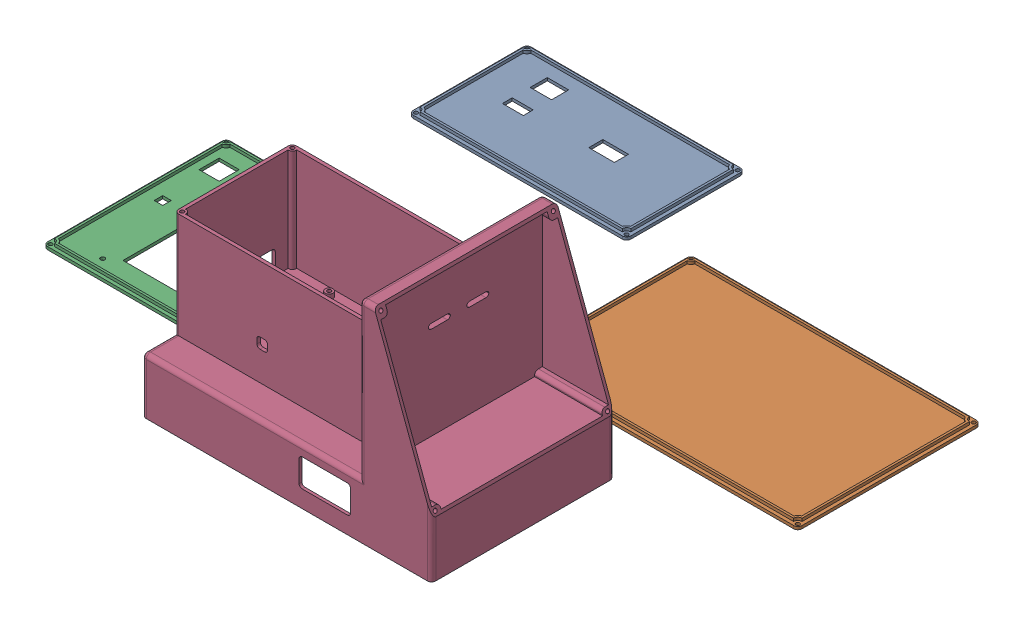
SolidWorks assembly Assembly PCB Box, configuration Default. Lengths in mm.
Overall size (370.19 125.12 303.92).
4 component instances, 4 part files, 4 mates.
Components (placement in the parent):
- pcb box lid-1: pcb box lid [Default] at (-27.4267 33.4367 83.8506) size (129.29 3.4 70.1)
- power supply lid-1: power supply lid [Default] at (129.7431 33.4367 181.9969) size (172.06 3.4 108.56)
- screen lid-1: screen lid [Default] at (-68.3866 33.4367 260.1209) size (96.52 3.4 108.56)
- pcb box main-3: pcb box main [Default] at (47.7522 66.4567 210.5523) size (172.06 125.12 108.56)
Mates (geometry in assembly coordinates):
- Coincident2: coincident aligned: plane of pcb box lid-1 through (-27.4267 31.7367 83.8506) normal (0 -1 0); plane of power supply lid-1 through (129.7431 31.7367 181.9969) normal (0 -1 0)
- Coincident3: coincident aligned: plane of power supply lid-1 through (129.7431 31.7367 181.9969) normal (0 -1 0); plane of screen lid-1 through (-68.3866 31.7367 260.1209) normal (0 -1 0)
- Coincident4: coincident aligned: plane of pcb box main-1 through (57.6241 31.7367 198.8777) normal (0 -1 0); plane of screen lid-1 through (-68.3866 31.7367 260.1209) normal (0 -1 0)
- Coincident5: coincident aligned: plane of power supply lid-1 through (129.7431 31.7367 181.9969) normal (0 -1 0); plane of pcb box main-3 through (47.7522 31.7367 210.5523) normal (0 -1 0)
